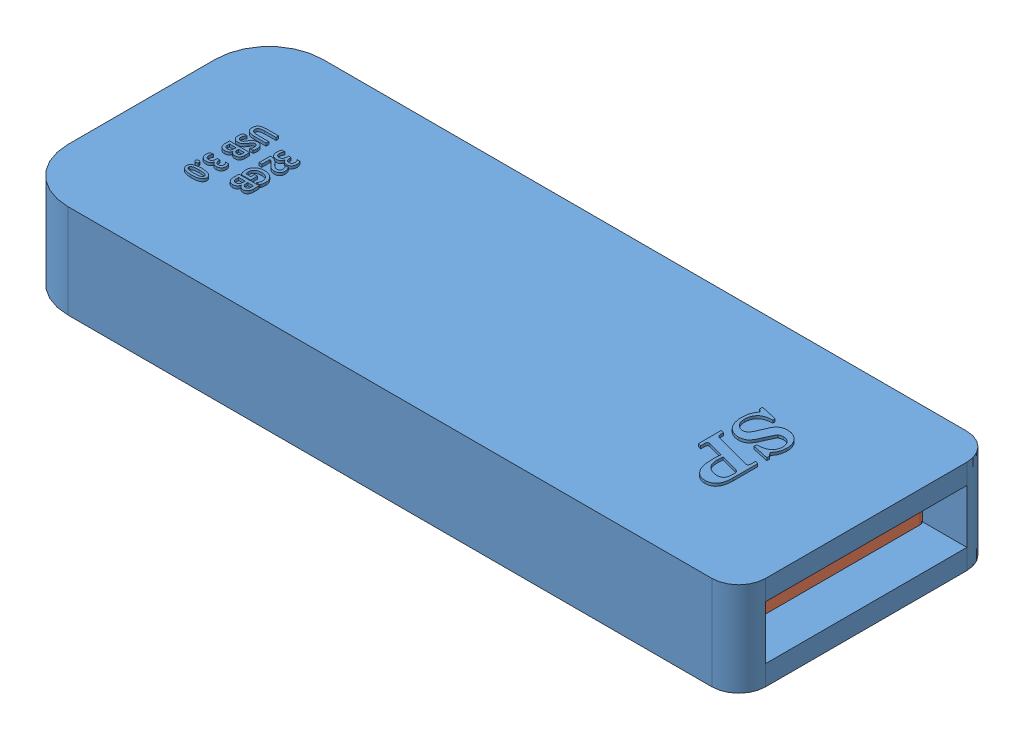
SolidWorks assembly USB Stick, configuration Default. Lengths in mm.
Overall size (54 7.2 19).
2 component instances, 2 part files, 9 mates.
Components (placement in the parent):
- Stick Cover-1: Stick Cover [Default] at (29.0282 20.9404 41.6869) size (54 7.2 19)
- Stick Insider-2: Stick Insider [Default] at (26.0282 26.4404 39.4869) size (49 5.5 14.8)
Mates (geometry in assembly coordinates):
- Coincident12: coincident anti-aligned: plane of Stick Cover-1 through (-20.9718 22.4404 24.6869) normal (0 0 1); plane of Stick Insider-2 through (26.0282 22.6404 24.6869) normal (0 0 -1)
- Parallel6: parallel anti-aligned: plane of Stick Cover-1 through (-20.9718 20.9404 41.6869) normal (1 0 0); plane of Stick Insider-2 through (-22.9718 22.6404 39.4869) normal (-1 0 0)
- Parallel7: parallel anti-aligned: plane of Stick Cover-1 through (-20.9718 20.9404 41.6869) normal (1 0 0); plane of Stick Insider-2 through (-22.9718 22.6404 39.4869) normal (-1 0 0)
- Parallel10: parallel aligned: plane of Stick Cover-1 through (-20.9718 22.4404 24.6869) normal (0 0 1); plane of Stick Insider-2 through (26.0282 22.6404 39.4869) normal (0 0 1)
- Coincident19: coincident anti-aligned: plane of Stick Cover-1 through (-20.9718 26.4404 24.6869) normal (0 -1 0); plane of Stick Insider-2 through (26.0282 26.4404 39.4869) normal (0 1 0)
- Parallel13: parallel anti-aligned: plane of Stick Cover-1 through (-20.9718 22.4404 39.6869) normal (0 1 0); plane of Stick Insider-2 through (26.0282 22.6404 39.4869) normal (0 -1 0)
- Parallel19: parallel anti-aligned: plane of Stick Cover-1 through (-7.9718 52.0724 36.6869) normal (0 0 -1); plane of Stick Insider-2 through (-7.9718 20.9404 35.5869) normal (0 0 1)
- Parallel20: parallel anti-aligned: plane of Stick Cover-1 through (16.0282 52.0724 27.6869) normal (-1 0 0); plane of Stick Insider-2 through (1.0282 20.9404 35.5869) normal (1 0 0)
- LimitDistance4: limit distance = 0 mm anti-aligned: plane of Stick Insider-2 through (-7.9718 20.9404 35.5869) normal (-1 0 0); plane of Stick Cover-1 through (-7.9718 52.0724 27.6869) normal (1 0 0)
